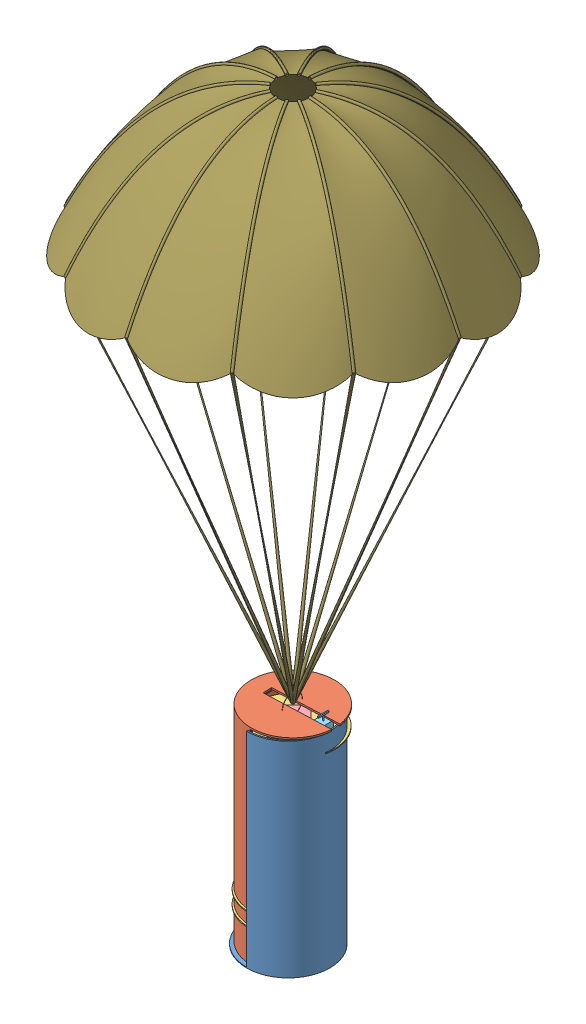
SolidWorks assembly Assem1, configuration Default. Lengths in mm.
Overall size (514.47 1116.32 514.47).
65 component instances, 41 part files, 1 mates.
Components (placement in the parent):
- Part1-1: Part1 [Default] at (164.1134 59.04 279.5706) size (125 308 125)
- Part2-1: Part2 [Default] at (165.6134 369.54 274.2292) x (0 0 -1) z (-1 0 0) size (125 308.5 124.87)
- Part3-1: Part3 [Default] at (164.4006 129.7882 279.3985) size (120 1.5 120)
- Part3-2: Part3 [Default] at (164.4006 109.7882 279.3985) size (120 1.5 120)
- Teensy_4.0_Assembly-1: Teensy_4.0_Assembly [Default] at (174.8371 101.1194 278.8874) x (0.008727 0 -0.999962) z (0.999962 0 0.008727) size (36.75 4.12 17.7)
  - Teensy_4.0_PCB-1: Teensy_4.0_PCB [Default] at (-32.9666 11.0804 9.3926) size (35.5 1.4 17.7)
  - Micro USB-B Female 5Pin SMD-1: Micro USB-B Female 5Pin SMD [Default] at (-46.3666 13.7054 9.3926) x (0 0 1) z (0 1 0) size (8.05 5.8 3.73)
  - NXP iMXRT1062-1: NXP iMXRT1062 [Default] at (-33.7166 12.4804 9.3926) x (0 0 1) z (-1 0 0) size (10 1.52 10)
  - SKRPACE010 v4-1: SKRPACE010 v4 [Default] at (-22.5666 12.5304 7.7926) size (4.89 2.55 3.2)
- XBee Pro 60mW-1: XBee Pro 60mW [Default] at (151.6393 68.6979 299.8831) size (33 30 25)
  - XBee Pro 60mW PCB-1: XBee Pro 60mW PCB [Default] at (-26.8117 -5.3484 14.4414) size (33 25 25)
  - 10x Pinheader Male-1: 10x Pinheader Male [Default] at (-19.6678 -5.3484 -9.4947) x (0 0 -1) z (-1 0 0) size (2 9 20)
  - 10x Pinheader Male-2: 10x Pinheader Male [Default] at (-19.6678 -5.3484 13.3775) x (0 0 -1) z (-1 0 0) size (2 9 20)
- battery-1: battery [Default] at (187.3751 69.539 255.8901) x (0.008727 0.999962 0) z (0 0 1) size (18.5 66.3 18.5)
- Holder-1: Holder [Default] at (154.5075 69.4832 256.1811) x (0.008727 0.999924 -0.008726) z (0.999962 -0.008726 0.000076) size (19.6 19.6 65.3)
- Para_2-1: Para_2 [Default] at (165.3738 970.6753 273.6883) size (514.47 802 514.47)
- Adafruit BMP388 Breakout.step-1: Adafruit BMP388 Breakout.step [Default] at (147.7903 115.3443 277.9721) size (21.59 11.6 16.51)
  - MalePinHeader.step-1: MalePinHeader.step [Default] at (14.8329 -4.1349 22.0117) size (2.54 11.54 2.54)
  - MalePinHeader.step-2: MalePinHeader.step [Default] at (9.7562 -4.1349 22.0162) size (2.54 11.54 2.54)
  - MalePinHeader.step-3: MalePinHeader.step [Default] at (7.2156 -4.1349 21.9989) size (2.54 11.54 2.54)
  - MalePinHeader.step-4: MalePinHeader.step [Default] at (-0.4008 -4.1349 21.997) size (2.54 11.54 2.54)
  - MalePinHeader.step-5: MalePinHeader.step [Default] at (-2.9499 -4.1349 22.0117) size (2.54 11.54 2.54)
  - MalePinHeader.step-6: MalePinHeader.step [Default] at (12.3028 -4.1349 22.0061) size (2.54 11.54 2.54)
  - MalePinHeader.step-7: MalePinHeader.step [Default] at (2.1379 -4.1349 22.0105) size (2.54 11.54 2.54)
  - MalePinHeader.step-8: MalePinHeader.step [Default] at (4.6865 -4.1349 22.0155) size (2.54 11.54 2.54)
  - Bosch BMP388.step-1: Bosch BMP388.step [Default] at (6.2406 0.0201 15.767) size (2 0.75 2)
  - SOD-523F Package.step-1: SOD-523F Package.step [Default] at (9.3077 0.02 14.6929) size (1.6 0.7 0.8)
  - SOT-23-5.step-1: SOT-23-5.step [Default] at (-0.8779 0.02 16.4671) x (0 0 -1) z (1 0 0) size (2.8 1.45 2.9)
  - SOT-363.step-1: SOT-363.step [Default] at (11.8928 0.77 18.7503) size (2.1 1.1 2)
  - 0603 Isolated 4 Resistor Array.step-1: 0603 Isolated 4 Resistor Array.step [Default] at (14.3354 0.02 15.5451) x (0 0 1) z (0 1 0) size (3.2 1.6 0.61)
  - Capacitor 0805 T1.35 BN.step-1: Capacitor 0805 T1.35 BN.step [Default] at (-1.0453 0.695 18.8902) size (2.1 1.35 1.35)
  - Capacitor 0805 T1.35 BN.step-2: Capacitor 0805 T1.35 BN.step [Default] at (1.1606 0.695 16.384) x (0 0 -1) z (1 0 0) size (2.1 1.35 1.35)
  - Capacitor 0603 T0.9 BN.step-1: Capacitor 0603 T0.9 BN.step [Default] at (3.9082 0.47 16.3763) x (0 0 1) z (-1 0 0) size (1.7 0.9 0.9)
  - Resistor 0603.step-1: Resistor 0603.step [Default] at (12.1248 -0.03 14.2385) size (1.7 0.55 0.9)
  - Resistor 0603.step-2: Resistor 0603.step [Default] at (6.6546 -0.03 18.7736) x (0 0 1) z (-1 0 0) size (1.7 0.55 0.9)
  - Adafruit BMP388 Breakout.step-1: Adafruit BMP388 Breakout.step [Default] at origin size (21.59 1.62 16.51)
- Quectel MC90.step-1: Quectel MC90.step [Default] at (142.0541 116.7937 272.7296) x (1 0 0) z (0 -0.999962 0.008727) size (15.02 25.62 2.3)
- Adafruit BNO055 STEMMA QT.step-1: Adafruit BNO055 STEMMA QT.step [Default] at (175.8717 115.9059 248.9272) x (1 0 0) z (0 -0.999391 -0.034899) size (25.4 20.32 4.6)
  - SOD-123.step-1: SOD-123.step [Default] at (7.2106 -3.9982 1.65) x (-1 0 0) z (0 0 1) size (3.85 1.7 1.36)
    - SOD-123_1.step-1: SOD-123_1.step [Default] at origin size (3.85 1.7 1.36)
      - Cathode.step-1: Cathode.step [Default] at origin size (1.45 0.65 0.7)
      - Anode.step-1: Anode.step [Default] at origin size (1.45 0.65 0.7)
      - Cathode Bar.step-1: Cathode Bar.step [Default] at origin size (0.3 1.5 0.01)
      - Body.step-1: Body.step [Default] at origin size (2.85 1.7 1.25)
  - Printed Circuit Board.step-1: Printed Circuit Board.step [Default] at origin size (25.4 20.32 1.65)
  - BNO055-9axis-IMU.step-1: BNO055-9axis-IMU.step [Default] at (-0.775 -1.2322 1.65) x (0 -1 0) z (0 0 1) size (5.2 3.8 1.18)
  - Crystal_XTAL3215_32.768KHz.step-1: Crystal_XTAL3215_32.768KHz.step [Default] at (2.5018 -0.2424 1.65) x (0 1 0) z (0 0 1) size (3.2 1.5 0.9)
  - SOT23-5.step-1: SOT23-5.step [Default] at (-5.3675 -3.3806 1.6297) x (0 -1 0) z (0 0 1) size (2.84 3.01 1.19)
  - SOT23-6.step-1: SOT23-6.step [Default] at (3.2455 -3.4306 1.2743) size (1.98 2.11 0.83)
  - LED 0603 single color.step-1: LED 0603 single color.step [Default] at (-11.0696 4.2146 1.6576) x (0 1 0) z (0 0 1) size (0.79 1.6 0.71)
  - CAPC-0805-T0.95-BN.step-1: CAPC-0805-T0.95-BN.step [Default] at (-4.9887 0.9204 1.65) size (2.1 1.35 0.95)
  - CAPC-0805-T0.95-BN.step-2: CAPC-0805-T0.95-BN.step [Default] at (-8.7494 -4.1689 1.65) size (2.1 1.35 0.95)
  - CAPC-0603-T0.9-BN.step-1: CAPC-0603-T0.9-BN.step [Default] at (-5.2459 -0.7391 1.65) size (1.7 0.9 0.9)
  - CAPC-0603-T0.9-BN.step-2: CAPC-0603-T0.9-BN.step [Default] at (2.199 2.9893 1.65) size (1.7 0.9 0.9)
  - CAPC-0603-T0.9-BN.step-3: CAPC-0603-T0.9-BN.step [Default] at (4.3017 -0.0333 1.65) x (0 1 0) z (0 0 1) size (1.7 0.9 0.9)
  - CAPC-0603-T0.9-BN.step-4: CAPC-0603-T0.9-BN.step [Default] at (5.6826 -0.393 1.65) x (0 1 0) z (0 0 1) size (1.7 0.9 0.9)
  - RESC-0603.step-1: RESC-0603.step [Default] at (10.9068 -4.1944 1.65) size (1.7 0.9 0.55)
  - YC164_RESPACK.step-1: YC164_RESPACK.step [Default] at (-3.6288 2.1707 1.65) size (3.2 1.6 0.61)
  - YC164_RESPACK.step-2: YC164_RESPACK.step [Default] at (7.5951 4.3154 1.65) x (-1 0 0) z (0 0 1) size (3.2 1.6 0.61)
  - qwicc.step-1: qwicc.step [Default] at (-8.624 0.0086 1.345) x (0 -1 0) z (-1 0 0) size (6 2.96 4.95)
  - qwicc.step-2: qwicc.step [Default] at (8.5749 0.0141 1.345) x (0 1 0) z (1 0 0) size (6 2.96 4.95)
- Part27-2: Part27 [Default] at (166.3009 370.24 275.8515) size (0.5 30 30)
- Part3-4: Part3 [Default] at (167.5376 340.4294 273.4135) size (120 1.5 120)
- Part4-1: Part4 [Default] at (162.7278 341.396 278.6621) size (60.41 10 60.41)
- Part5-1: Part5 [Default] at (208.0669 337.5734 270.8175) size (15 39 16)
Mates (geometry in assembly coordinates):
- Coincident8: coincident anti-aligned: plane of Part1-1 through (164.1134 367.04 279.5706) normal (0 1 0); plane of Part2-1 through (165.6134 367.04 274.2292) normal (0 -1 0)
